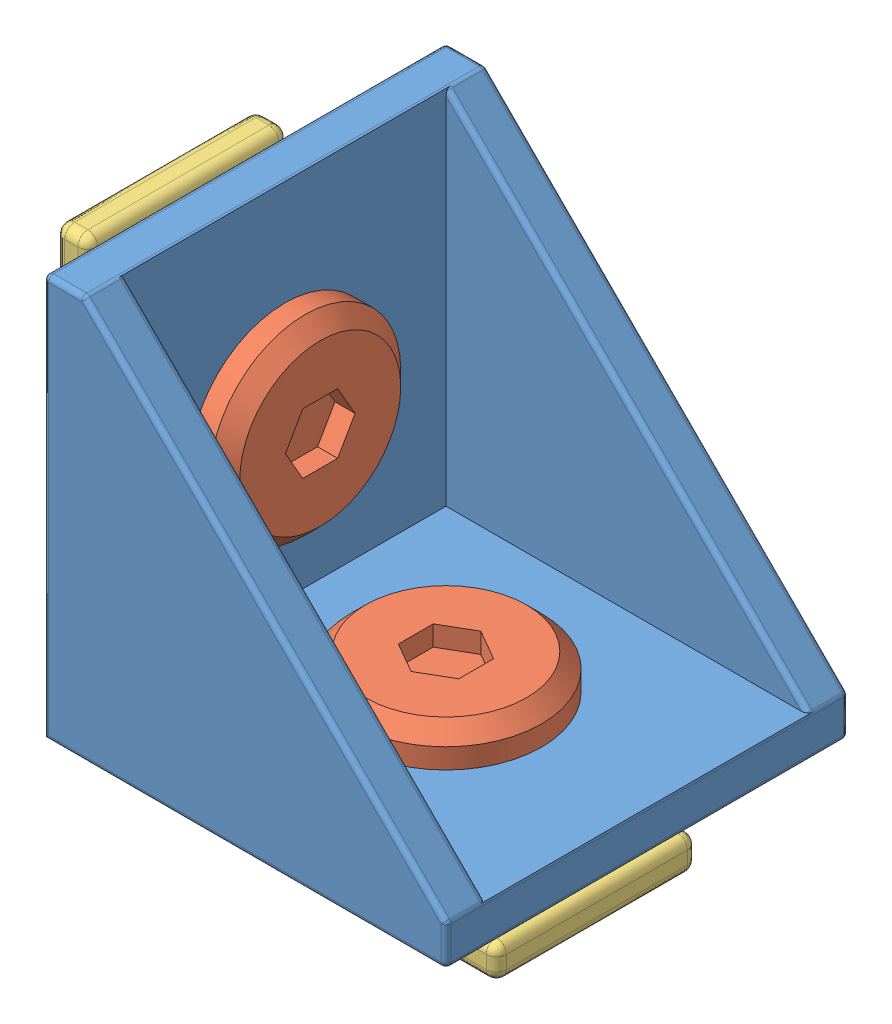
SolidWorks assembly stageCorner, configuration Standard. Lengths in mm.
Overall size (26.35 26.35 20).
7 component instances, 3 part files, 8 mates.
Components (placement in the parent):
- Cast - 90 Degree Corner Bracket-1: Cast - 90 Degree Corner Bracket [Default] at origin size (20.75 20.75 20)
- 5mm x 8mm Bolt with Tee Nut-1: 5mm x 8mm Bolt with Tee Nut [Default] at (-31.0938 20.4769 7.7195) x (-1 0 0) z (0 -1 0) size (10.1 10 15)
  - 5mm x 8mm Low Profile Socket Head Screw-1: 5mm x 8mm Low Profile Socket Head Screw [5mm x 8mm Low Profile] at (-34.8438 7.7195 10.4769) size (10.1 9.5 9.5)
  - Tee nut-1: Tee nut [Default] at (-28.2938 2.7205 17.9769) x (0 0 -1) z (1 0 0) size (15 10 3.3)
- 5mm x 8mm Bolt with Tee Nut-2: 5mm x 8mm Bolt with Tee Nut [Default] at (-0.4769 -31.0938 7.7195) x (0 -1 0) z (1 0 0) size (10.1 10 15)
  - 5mm x 8mm Low Profile Socket Head Screw-1: 5mm x 8mm Low Profile Socket Head Screw [5mm x 8mm Low Profile] at (-34.8438 7.7195 10.4769) size (10.1 9.5 9.5)
  - Tee nut-1: Tee nut [Default] at (-28.2938 2.7205 17.9769) x (0 0 -1) z (1 0 0) size (15 10 3.3)
Mates (geometry in assembly coordinates):
- Coincident3: coincident anti-aligned: plane of Cast - 90 Degree Corner Bracket-1 through (2 0 10) normal (1 0 0); plane of 5mm x 8mm Bolt with Tee Nut-1/5mm x 8mm Low Profile Socket Head Screw-1 through (2 12.75 -2.5) normal (-1 0 0)
- Coincident4: coincident anti-aligned: plane of Cast - 90 Degree Corner Bracket-1 through (-24.0832 2 8) normal (0 1 0); plane of 5mm x 8mm Bolt with Tee Nut-2/5mm x 8mm Low Profile Socket Head Screw-1 through (12.75 2 -2.5) normal (0 -1 0)
- Parallel5: parallel: plane of Cast - 90 Degree Corner Bracket-1 through (0.25 19.75 10) normal (0 0 1); line of 5mm x 8mm Bolt with Tee Nut-1/Tee nut-1 through (-3.3 5.75 4.999) axis (0 1 0)
- Parallel6: parallel: plane of Cast - 90 Degree Corner Bracket-1 through (0.25 19.75 10) normal (0 0 1); line of 5mm x 8mm Bolt with Tee Nut-2/Tee nut-1 through (5.75 -3.95 4.999) axis (1 0 0)
- Coincident7: coincident anti-aligned: unknown of ?
- Distance1: distance = 10 mm aligned: plane of 5mm x 8mm Bolt with Tee Nut-2/5mm x 8mm Low Profile Socket Head Screw-1 through (10 3.75 0) normal (1 0 0); plane of assembly
- Coincident8: coincident anti-aligned: unknown of ?
- Distance2: distance = 10 mm anti-aligned: plane of 5mm x 8mm Bolt with Tee Nut-1/5mm x 8mm Low Profile Socket Head Screw-1 through (3.75 10 0) normal (0 -1 0); plane of assembly
